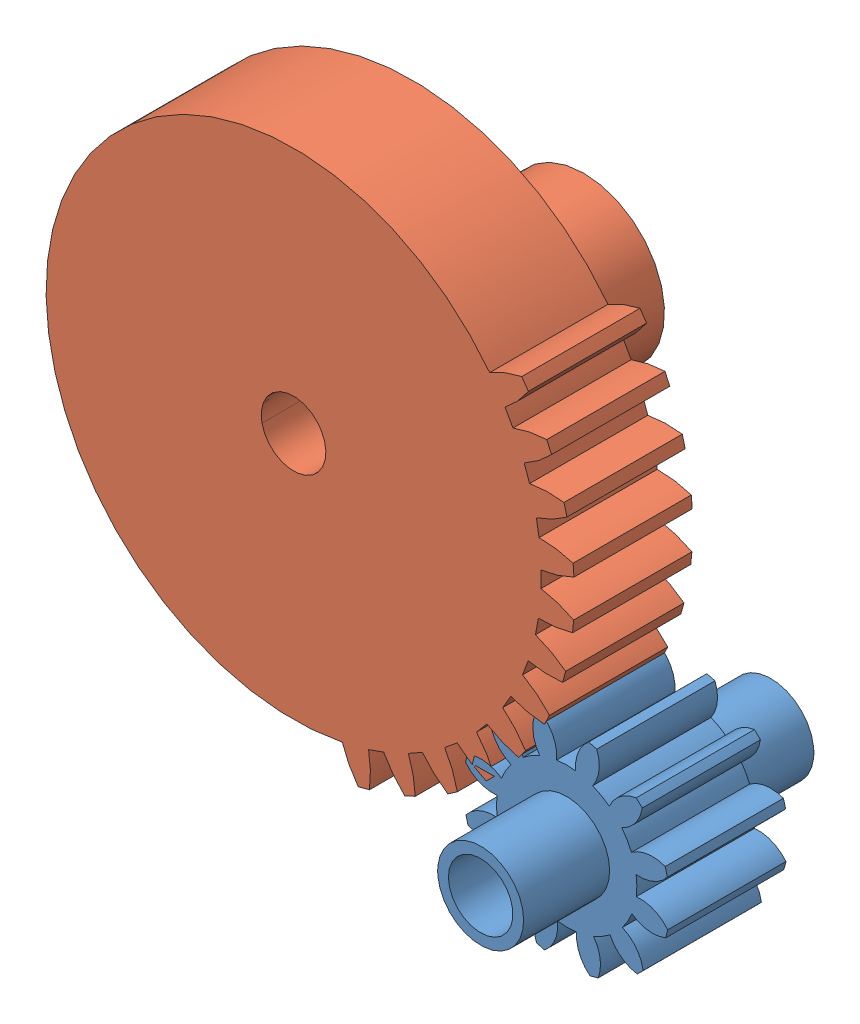
SolidWorks assembly gears 1, configuration Default. Lengths in mm.
Overall size (61.36 56.97 35).
2 component instances, 2 part files, 5 mates.
Components (placement in the parent):
- spur gear_am-3: spur gear_am [Metric - Spur gear 1.375M 12T 14.5PA 11FW ---S12B8H27L6N] at (34.6667 0 11) x (0 0 -1) z (-0.999975 -0.007046 0) size (27 18.78 18.78)
- big spur-1: big spur [Default] at (12.6363 23.1331 -6.996) x (0 0 1) z (0.98635 0.164665 0) size (27 49.1 49.1)
Mates (geometry in assembly coordinates):
- Coincident1: coincident: plane of spur gear_am-3 through (34.6667 0 0) normal (0 0 -1); plane of assembly through (0 0 0) normal (0 0 1)
- Concentric2: concentric: circle of spur gear_am-3; circle of assembly
- Coincident3: coincident: plane of spur gear_am-3 through (34.6667 0 11) normal (0 0 1); plane of big spur-1 through (13.5695 -5.261 11) normal (0 0 1)
- Distance1: distance = 32.66 mm: point of assembly; point of big spur-1
- GearMate1: gear = 6 : 6 mm: cylinder of big spur-1 through (9.2676 20.5074 11) axis (0 0 1) radius 3; cylinder of spur gear_am-3 through (34.6667 0 -16.0001) axis (0 0 1) radius 3
